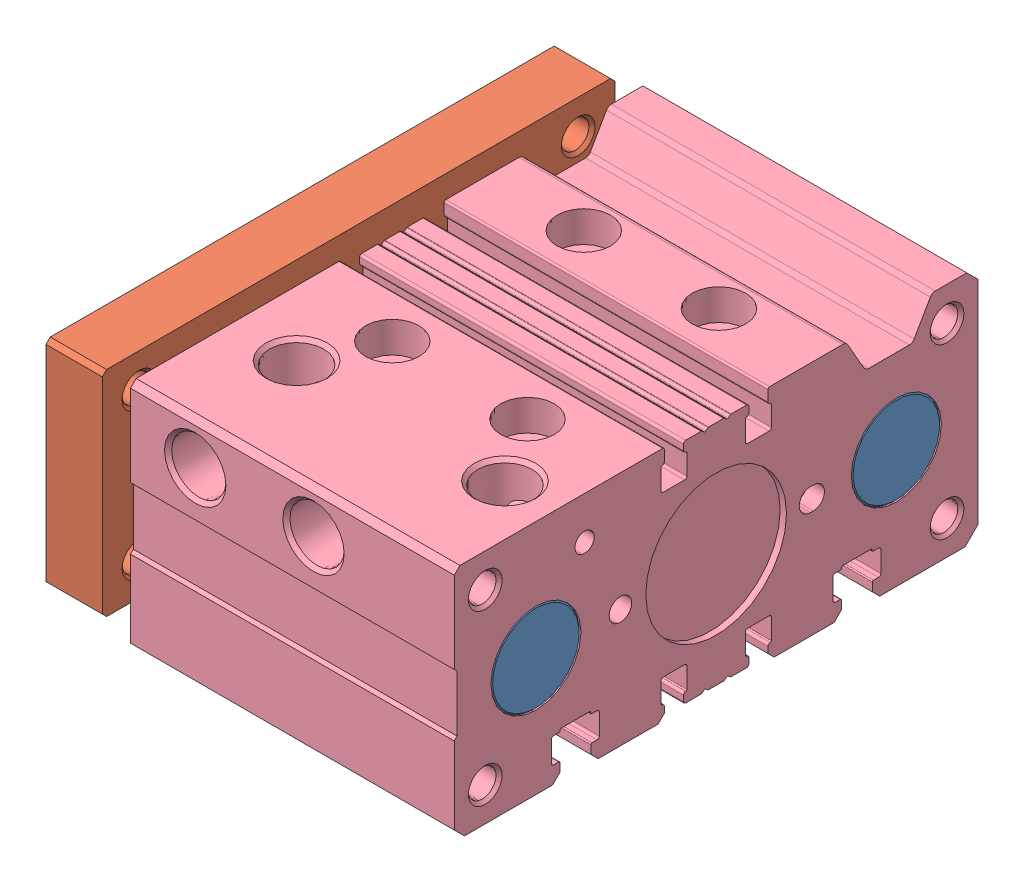
SolidWorks assembly MTCM-25X20-S-T.stp, configuration Default. Lengths in mm.
Overall size (73.5 42 93).
5 component instances, 4 part files, 0 mates.
Components (placement in the parent):
- MTCM-25X20-S-T-0_guide_shaft.stp-1: MTCM-25X20-S-T-0_guide_shaft.stp [Default] at (-8 0 32) size (72.56 16 16)
- MTCM-25X20-S-T-0_guide_shaft.stp-2: MTCM-25X20-S-T-0_guide_shaft.stp [Default] at (-8 0 -32) size (72.56 16 16)
- MTCM-25X20-S-T_plate.stp-1: MTCM-25X20-S-T_plate.stp [Default] at (-6 0 0) size (10 38 91)
- MTCM-25X20-S-T-0_guide_rod.stp-1: MTCM-25X20-S-T-0_guide_rod.stp [Default] at (-8 0 0) size (68.06 25 25)
- MTCM-25X20-S-T-0_body.stp-1: MTCM-25X20-S-T-0_body.stp [Default] at origin size (57.5 42 93)
